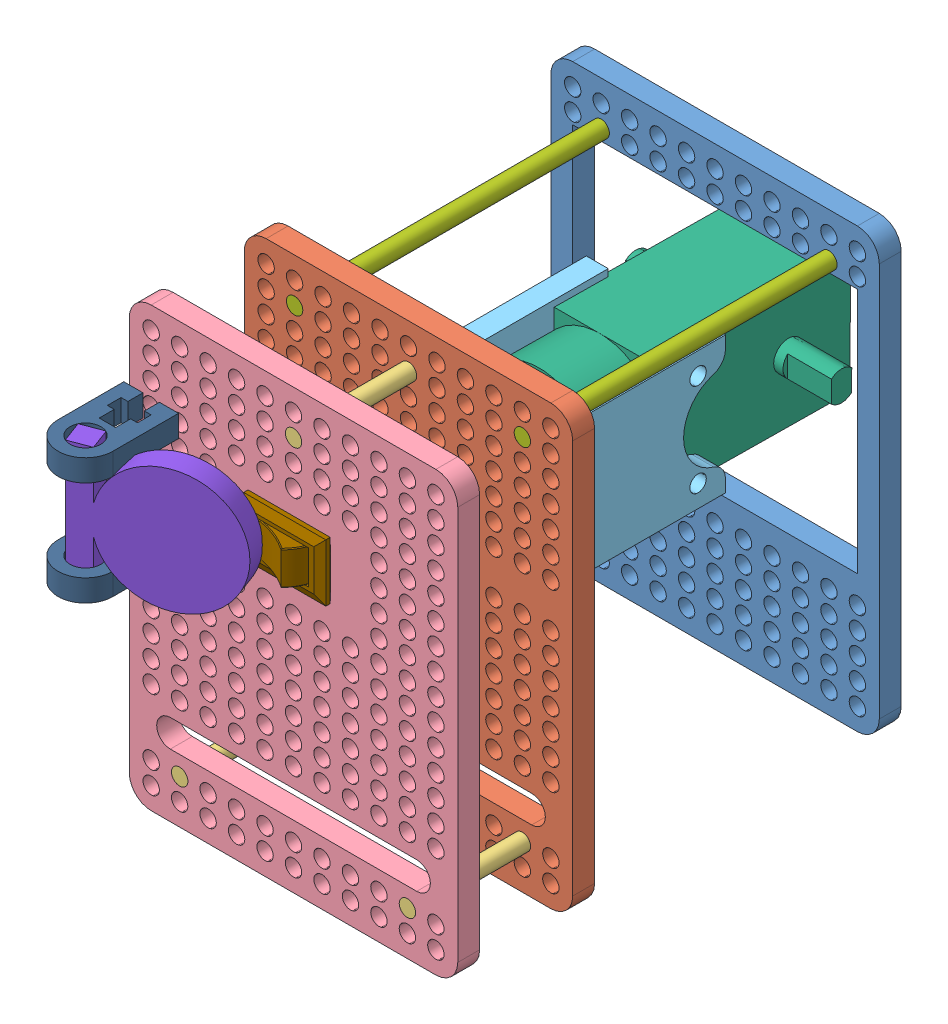
SolidWorks assembly Сборка2 коровы, configuration По умолчанию. Lengths in mm.
Overall size (61 80 115.93).
15 component instances, 10 part files, 41 mates.
Components (placement in the parent):
- инвалид основа 2026 (корова)-1: инвалид основа 2026 (корова) [По умолчанию] at (0.0445 0.0075 78) size (60 80 4)
- середина корова инвалид-1: середина корова инвалид [По умолчанию] at (0.0445 0.0075 134) size (60 80 4)
- шпилька 25мм для ненужной сборки-1: шпилька 25мм для ненужной сборки [По умолчанию] at (30.0445 72.0075 134) size (3 3 25)
- шпилька 25мм для ненужной сборки-2: шпилька 25мм для ненужной сборки [По умолчанию] at (50.8445 8.0075 134) size (3 3 25)
- шпилька 25мм для ненужной сборки-3: шпилька 25мм для ненужной сборки [По умолчанию] at (9.2445 8.0075 134) size (3 3 25)
- верхняя часть короввы-1: верхняя часть короввы [По умолчанию] at (0.0445 0.0075 155) size (60 80 4)
- держатель мотора-2: держатель мотора [По умолчанию] at (41.9445 60.7396 92) x (0 -1 0) z (-1 0 0) size (25 42 4)
- держатель мотора-3: держатель мотора [По умолчанию] at (16.5311 35.5075 92) x (0 1 0) z (1 0 0) size (25 42 4)
- Мотор с редуктором-2: Мотор с редуктором [По умолчанию] at (19.7445 36.3275 65.3305) x (0 0.011392 0.999935) z (-1 0 0) size (70.5 22.73 37.6)
- шпилька60мм для не нужной сборки-5: шпилька60мм для не нужной сборки [По умолчанию] at (9.2445 72.0075 78) size (3 3 60)
- шпилька60мм для не нужной сборки-7: шпилька60мм для не нужной сборки [По умолчанию] at (50.8445 72.0075 78) size (3 3 60)
- красная кнопка-1: красная кнопка [По умолчанию] at (1.5056 42.3732 169.8194) x (0.935781 0 -0.352583) z (0.352583 0 0.935781) size (26.18 23 4)
- MINI SWITCH-1: MINI SWITCH [По умолчанию] at (29.2445 54.3575 159) size (15 10.5 19.39)
- держатель красной кнопки-3: держатель красной кнопки [По умолчанию] at (-0.9555 46.3732 159) x (1 0 0) z (0 -1 0) size (10 17 4)
- держатель красной кнопки-4: держатель красной кнопки [По умолчанию] at (9.0445 61.3732 159) x (-1 0 0) z (0 1 0) size (10 17 4)
Mates (geometry in assembly coordinates):
- Совпадение5: coincident anti-aligned: plane of середина корова инвалид-1 through (4.0445 76.0075 134) normal (0 0 -1); circle of шпилька 25мм для ненужной сборки-1
- Совпадение6: coincident anti-aligned: cylinder of середина корова инвалид-1; cylinder of шпилька 25мм для ненужной сборки-1 through (30.0445 72.0075 159) axis (0 0 -1) radius 1.5
- Совпадение7: coincident aligned: plane of середина корова инвалид-1 through (4.0445 76.0075 134) normal (0 0 -1); plane of шпилька 25мм для ненужной сборки-2 through (50.8445 8.0075 134) normal (0 0 -1)
- Концентричный6: concentric anti-aligned: cylinder of середина корова инвалид-1 through (50.8445 8.0075 134) axis (0 0 1) radius 1.5; cylinder of шпилька 25мм для ненужной сборки-2 through (50.8445 8.0075 159) axis (0 0 -1) radius 1.5
- Совпадение8: coincident anti-aligned: plane of середина корова инвалид-1 through (4.0445 76.0075 134) normal (0 0 -1); circle of шпилька 25мм для ненужной сборки-3
- Концентричный7: concentric anti-aligned: cylinder of середина корова инвалид-1 through (9.2445 8.0075 134) axis (0 0 1) radius 1.5; cylinder of шпилька 25мм для ненужной сборки-3 through (9.2445 8.0075 159) axis (0 0 -1) radius 1.5
- Совпадение9: coincident aligned: plane of шпилька 25мм для ненужной сборки-3 through (9.2445 8.0075 159) normal (0 0 1); plane of верхняя часть короввы-1 through (4.0445 76.0075 159) normal (0 0 1)
- Концентричный8: concentric anti-aligned: cylinder of шпилька 25мм для ненужной сборки-3 through (9.2445 8.0075 159) axis (0 0 -1) radius 1.5; cylinder of верхняя часть короввы-1 through (9.2445 8.0075 155) axis (0 0 1) radius 1.5
- Концентричный9: concentric anti-aligned: cylinder of шпилька 25мм для ненужной сборки-2 through (50.8445 8.0075 159) axis (0 0 -1) radius 1.5; cylinder of верхняя часть короввы-1 through (50.8445 8.0075 155) axis (0 0 1) radius 1.5
- Совпадение18: coincident anti-aligned: plane of середина корова инвалид-1 through (4.0445 76.0075 134) normal (0 0 -1); plane of держатель мотора-3 through (20.5311 35.5075 134) normal (0 0 1)
- Параллельность2: parallel aligned: plane of середина корова инвалид-1 through (0.0445 4.0075 138) normal (-1 0 0); plane of держатель мотора-3 through (16.5311 58.2263 95) normal (-1 0 0)
- Касательность7: tangent: cylinder of середина корова инвалид-1 through (19.6445 48.0075 134) axis (0 0 1) radius 1.5; plane of держатель мотора-3 through (20.1583 49.5075 134) normal (0 -1 0)
- Совпадение20: coincident anti-aligned: circle of держатель мотора-2; circle of Мотор с редуктором-2
- Совпадение31: coincident aligned: cylinder of инвалид основа 2026 (корова)-1 through (9.2445 72.0075 78) axis (0 0 1) radius 1.5; circle of шпилька60мм для не нужной сборки-5
- Совпадение32: coincident anti-aligned: plane of инвалид основа 2026 (корова)-1 through (4.0445 4.0075 78) normal (0 0 -1); circle of шпилька60мм для не нужной сборки-5
- Концентричный10: concentric anti-aligned: cylinder of середина корова инвалид-1 through (9.2445 72.0075 134) axis (0 0 1) radius 1.5; cylinder of шпилька60мм для не нужной сборки-5 through (9.2445 72.0075 138) axis (0 0 -1) radius 1.5
- Совпадение33: coincident aligned: circle of середина корова инвалид-1; plane of шпилька60мм для не нужной сборки-5 through (9.2445 72.0075 138) normal (0 0 1)
- Совпадение34: coincident aligned: cylinder of инвалид основа 2026 (корова)-1 through (50.8445 72.0075 78) axis (0 0 1) radius 1.5; circle of шпилька60мм для не нужной сборки-7
- Совпадение35: coincident anti-aligned: plane of инвалид основа 2026 (корова)-1 through (4.0445 4.0075 78) normal (0 0 -1); circle of шпилька60мм для не нужной сборки-7
- Концентричный11: concentric anti-aligned: cylinder of середина корова инвалид-1 through (50.8445 72.0075 134) axis (0 0 1) radius 1.5; cylinder of шпилька60мм для не нужной сборки-7 through (50.8445 72.0075 138) axis (0 0 -1) radius 1.5
- Параллельность3: parallel aligned: plane of держатель мотора-2 through (41.9445 38.0208 95) normal (1 0 0); plane of Мотор с редуктором-2 through (38.9445 52.8356 105.4544) normal (1 0 0)
- Касательность13: tangent: cylinder of середина корова инвалид-1 through (19.6445 48.0075 134) axis (0 0 1) radius 1.5; plane of держатель мотора-3 through (20.1583 49.5075 134) normal (0 -1 0)
- Совпадение37: coincident anti-aligned: plane of середина корова инвалид-1 through (4.0445 76.0075 134) normal (0 0 -1); plane of держатель мотора-2 through (37.9445 46.7396 134) normal (0 0 1)
- Касательность14: tangent aligned: cylinder of середина корова инвалид-1 through (40.4445 48.0075 134) axis (0 0 1) radius 1.5; plane of держатель мотора-2 through (41.9445 38.0208 95) normal (1 0 0)
- Совпадение38: coincident anti-aligned: plane of середина корова инвалид-1 through (4.0445 76.0075 134) normal (0 0 -1); plane of держатель мотора-3 through (20.5311 49.5075 134) normal (0 0 1)
- Касательность15: tangent: cylinder of середина корова инвалид-1 through (24.8445 48.0075 134) axis (0 0 1) radius 1.5; plane of держатель мотора-3 through (20.5311 46.5075 134) normal (0 1 0)
- Касательность16: tangent anti-aligned: cylinder of середина корова инвалид-1 through (19.6445 48.0075 134) axis (0 0 1) radius 1.5; plane of держатель мотора-3 through (20.5311 46.5075 134) normal (0 1 0)
- Совпадение47: coincident anti-aligned: plane of верхняя часть короввы-1 through (4.0445 76.0075 159) normal (0 0 1); plane of MINI SWITCH-1 through (29.2445 54.3575 159) normal (0 0 -1)
- Совпадение48: coincident anti-aligned: plane of верхняя часть короввы-1 through (23.2945 58.5075 142) normal (1 0 0); plane of MINI SWITCH-1 through (23.2945 58.5075 153.1) normal (-1 0 0)
- Совпадение49: coincident anti-aligned: plane of верхняя часть короввы-1 through (23.2945 58.5075 142) normal (0 -1 0); plane of MINI SWITCH-1 through (22.7445 58.5075 156.5) normal (0 1 0)
- Совпадение56: coincident anti-aligned: plane of верхняя часть короввы-1 through (4.0445 76.0075 159) normal (0 0 1); plane of держатель красной кнопки-3 through (-0.9555 42.0206 159) normal (0 0 -1)
- Касательность20: tangent anti-aligned: cylinder of верхняя часть короввы-1 through (4.0445 40.0075 155) axis (0 0 1) radius 1.5; plane of держатель красной кнопки-3 through (2.5445 42.0206 159) normal (1 0 0)
- Параллельность5: parallel aligned: plane of верхняя часть короввы-1 through (0.0445 4.0075 159) normal (-1 0 0); plane of держатель красной кнопки-3 through (-0.9555 42.0206 159) normal (-1 0 0)
- Касательность22: tangent anti-aligned: cylinder of верхняя часть короввы-1 through (4.0445 64.0075 155) axis (0 0 1) radius 1.5; plane of держатель красной кнопки-4 through (5.5445 65.3732 159) normal (-1 0 0)
- Параллельность6: parallel aligned: plane of верхняя часть короввы-1 through (0.0445 4.0075 159) normal (-1 0 0); plane of держатель красной кнопки-4 through (-0.9555 65.3732 159) normal (-1 0 0)
- Совпадение61: coincident anti-aligned: plane of верхняя часть короввы-1 through (4.0445 76.0075 159) normal (0 0 1); plane of держатель красной кнопки-4 through (2.5445 65.3732 159) normal (0 0 -1)
- Касательность23: tangent anti-aligned: cylinder of верхняя часть короввы-1 through (4.0445 64.0075 155) axis (0 0 1) radius 1.5; plane of держатель красной кнопки-4 through (5.5445 65.3732 159) normal (-1 0 0)
- Совпадение62: coincident: line of красная кнопка-1 through (1.5056 65.3732 169.8194) axis (0 -1 0); cylinder of держатель красной кнопки-4 through (4.0445 55.3732 171) axis (0 1 0) radius 2.8
- Совпадение63: coincident aligned: plane of красная кнопка-1 through (2.9159 65.3732 173.5625) normal (0 1 0); plane of держатель красной кнопки-4 through (4.0445 65.3732 171) normal (0 1 0)
- Совпадение64: coincident: line of красная кнопка-1 through (2.9159 65.3732 173.5625) axis (0 -1 0); cylinder of держатель красной кнопки-4 through (4.0445 55.3732 171) axis (0 1 0) radius 2.8
- Совпадение65: coincident aligned: plane of красная кнопка-1 through (2.9159 42.3732 173.5625) normal (0 -1 0); plane of держатель красной кнопки-3 through (4.0445 42.3732 171) normal (0 -1 0)
